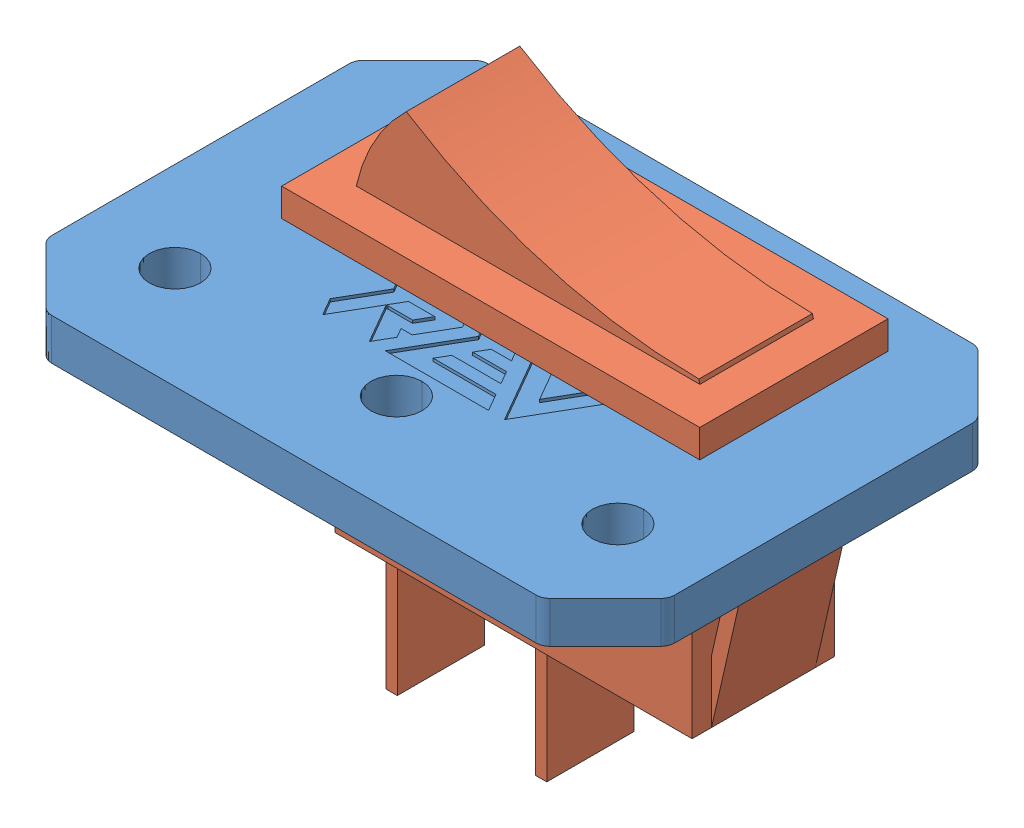
SolidWorks assembly REV-31-1387, configuration Default. Lengths in mm.
Overall size (45 38.06 31.5).
3 component instances, 2 part files, 0 mates.
Components (placement in the parent):
- REV-31-1387.STEP-1: REV-31-1387.STEP [Default] at origin size (45 38.06 31.5)
  - REV-31-1387-1.STEP-1: REV-31-1387-1.STEP [Default] at origin size (45 3 31.5)
  - Switch.STEP-1: Switch.STEP [Default] at (-0.15 -7.168 -5.4125) size (32.44 38.06 13.6)
